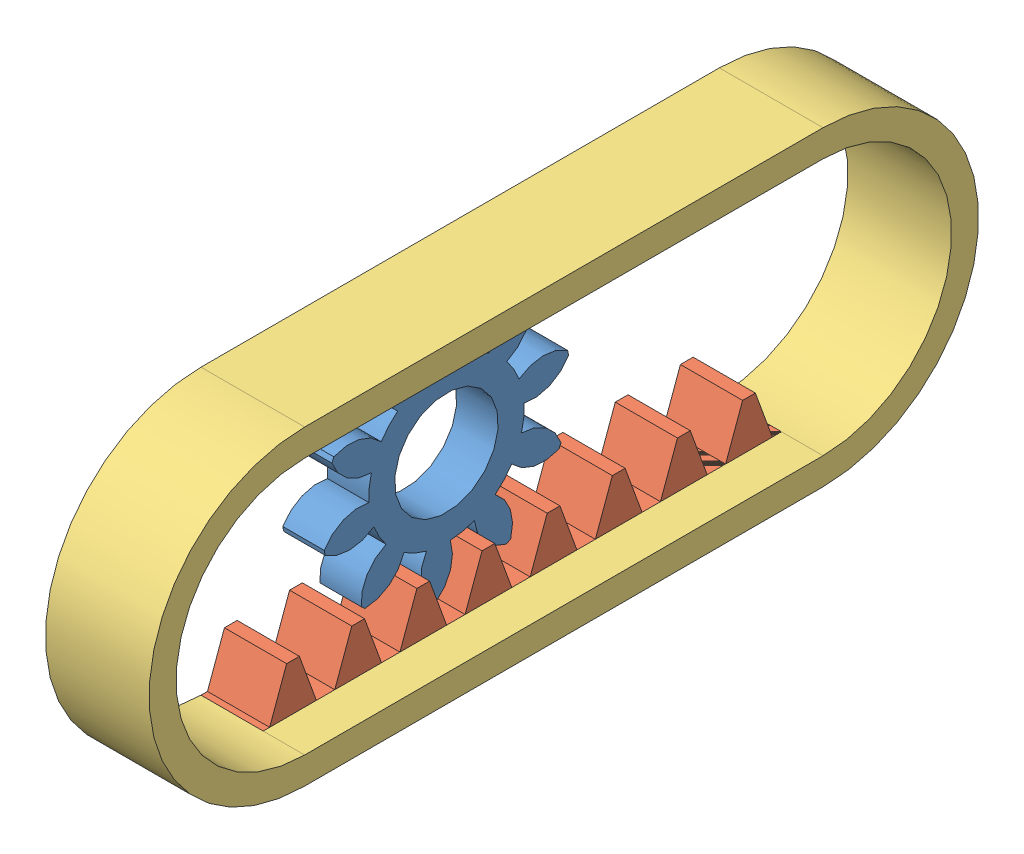
SolidWorks assembly Assem6, configuration Default. Lengths in mm.
Overall size (5 107.85 66.4).
3 component instances, 3 part files, 6 mates.
Components (placement in the parent):
- spur gear_am-1: spur gear_am [Metric - Spur gear 1M 10T 20PA 2FW ---S10N75H50L5N] at (-23.894 -9.4178 12.8485) x (-1 0 0) z (0 -0.407333 -0.91328) size (2 112.74 12)
- rack spur rectangular_am-1: rack spur rectangular_am [Metric - Rack-spur - rectangular 1M 20PA 3FW 2PH 25L---SAll] at (-25.894 -16.3678 -2.3134) x (0 0 1) z (-1 0 0) size (25 3 3)
- loop-1: loop [Default] at (-20.894 -9.4178 22.6866) x (0 0 -1) z (0 1 0) size (40 5 15)
Mates (geometry in assembly coordinates):
- Coincident1: coincident aligned: plane of rack spur rectangular_am-1 through (-22.894 -15.6178 20.1222) normal (0 1 0); plane of loop-1 through (-25.894 -15.6178 22.6866) normal (0 1 0)
- Coincident2: coincident aligned: plane of rack spur rectangular_am-1 through (-25.894 -13.3678 -2.3134) normal (-1 0 0); plane of loop-1 through (-25.894 -9.4178 22.6866) normal (-1 0 0)
- Coincident3: coincident anti-aligned: line of rack spur rectangular_am-1 through (-22.894 -15.6178 -2.3134) axis (-1 0 0); line of loop-1 through (-25.894 -15.6178 -2.3134) axis (1 0 0)
- Coincident5: coincident aligned: plane of spur gear_am-1 through (-25.894 -9.4178 12.8485) normal (-1 0 0); plane of loop-1 through (-25.894 -9.4178 22.6866) normal (-1 0 0)
- Distance1: distance = 6.2 mm: plane of rack spur rectangular_am-1 through (-22.894 -15.6178 20.1222) normal (0 1 0); cylinder of spur gear_am-1 through (-73.8941 -9.4178 12.8485) axis (1 0 0) radius 2.5
- RackPinionMate2: rack pinion = 10 mm: line of loop-1 through (-25.894 -16.9178 -2.3134) axis (0 0 1); circle of spur gear_am-1
